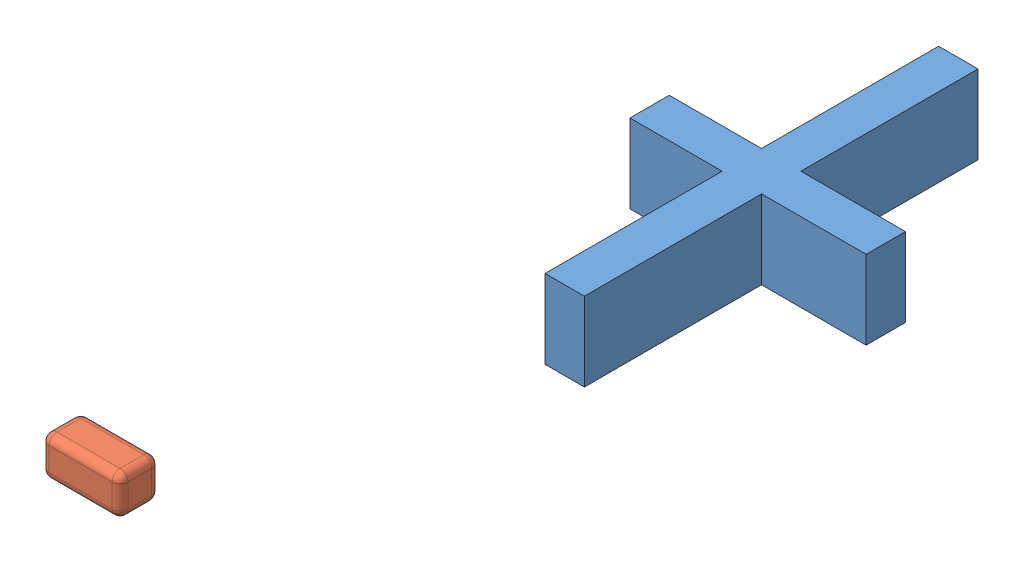
SolidWorks assembly Assem2, configuration Default. Lengths in mm.
Overall size (541.31 262.9 781.43).
2 component instances, 2 part files, 0 mates.
Components (placement in the parent):
- Tyre Joining Mechanism-1: Tyre Joining Mechanism [Default] at (187.7775 136.8647 399.5385) size (300 100 500)
- Tyre joining Mechanism 2-1: Tyre joining Mechanism 2 [Default] at (-153.5301 -26.0318 905.9699) size (100 50 50)
